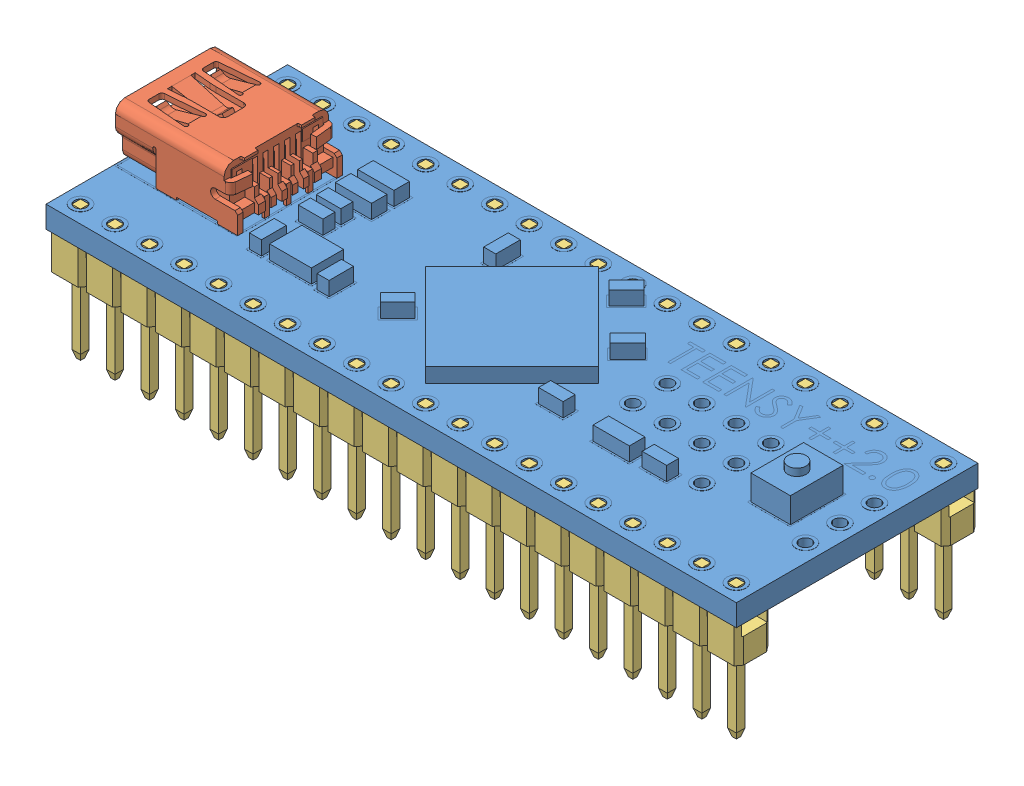
SolidWorks assembly Teensy++2.0, configuration Default. Lengths in mm.
Overall size (50.9 13.76 17.78).
4 component instances, 3 part files, 9 mates.
Components (placement in the parent):
- Base PCB^Teensy++2.0-1: Base PCB^Teensy++2.0 [Default] x (1 0 0) z (0 1 0) size (50.8 17.78 3.99) (virtual)
- USB-Mini-B^Teensy++2.0-1: USB-Mini-B^Teensy++2.0 [Default] at (0.2046 3.6002 -9.0779) x (0 0 1) z (-1 0 0) size (7.7 5.76 9) (virtual)
- 0.1 Pin Header^Teensy++2.0-1: 0.1 Pin Header^Teensy++2.0 [Default] at (25.5411 0 -16.6979) size (50.8 9.8 2.5) (virtual)
- 0.1 Pin Header^Teensy++2.0-3: 0.1 Pin Header^Teensy++2.0 [Default] at (25.5411 0 -1.4579) size (50.8 9.8 2.5) (virtual)
Mates (geometry in assembly coordinates):
- Coincident1: coincident anti-aligned: plane of Base PCB^Teensy++2.0-1 through (0 1.6002 0) normal (0 1 0); plane of USB-Mini-B^Teensy++2.0-1 through (2.9546 1.6002 -5.2279) normal (0 -1 0)
- Coincident2: coincident: line of Base PCB^Teensy++2.0-1 through (9.2046 1.6027 -12.9914) axis (0 0 1); plane of USB-Mini-B^Teensy++2.0-1 through (9.2046 5.5502 -12.2279) normal (1 0 0)
- Width1: width anti-aligned: plane of USB-Mini-B^Teensy++2.0-1 through (0.2046 4.0536 -12.9279) normal (0 0 -1); plane of USB-Mini-B^Teensy++2.0-1 through (0.2046 4.8502 -5.2279) normal (0 0 1); plane of Base PCB^Teensy++2.0-1 through (50.9411 1.6002 -0.1879) normal (0 0 1); plane of Base PCB^Teensy++2.0-1 through (50.9411 1.6002 -17.9679) normal (0 0 -1)
- Concentric3: concentric aligned: cylinder of Base PCB^Teensy++2.0-1 through (49.6711 1.6002 -16.6979) axis (0 -1 0) radius 0.4445; line of 0.1 Pin Header^Teensy++2.0-1 through (49.6711 3 -16.6979) axis (0 -1 0)
- Concentric4: concentric anti-aligned: cylinder of Base PCB^Teensy++2.0-1 through (1.4111 1.6002 -16.6979) axis (0 -1 0) radius 0.4445; line of 0.1 Pin Header^Teensy++2.0-1 through (1.4111 -8.2 -16.6979) axis (0 1 0)
- Coincident9: coincident anti-aligned: plane of Base PCB^Teensy++2.0-1 through (0 0 0) normal (0 -1 0); plane of 0.1 Pin Header^Teensy++2.0-1 through (0.297 0 -17.9437) normal (0 1 0)
- Concentric5: concentric aligned: cylinder of Base PCB^Teensy++2.0-1 through (49.6711 1.6002 -1.4579) axis (0 -1 0) radius 0.4445; line of 0.1 Pin Header^Teensy++2.0-3 through (49.6711 3 -1.4579) axis (0 -1 0)
- Concentric6: concentric anti-aligned: cylinder of Base PCB^Teensy++2.0-1 through (1.4111 1.6002 -1.4579) axis (0 -1 0) radius 0.4445; line of 0.1 Pin Header^Teensy++2.0-3 through (1.4111 -8.2 -1.4579) axis (0 1 0)
- Coincident10: coincident anti-aligned: plane of Base PCB^Teensy++2.0-1 through (0 0 0) normal (0 -1 0); plane of 0.1 Pin Header^Teensy++2.0-3 through (0.297 0 -2.7037) normal (0 1 0)
